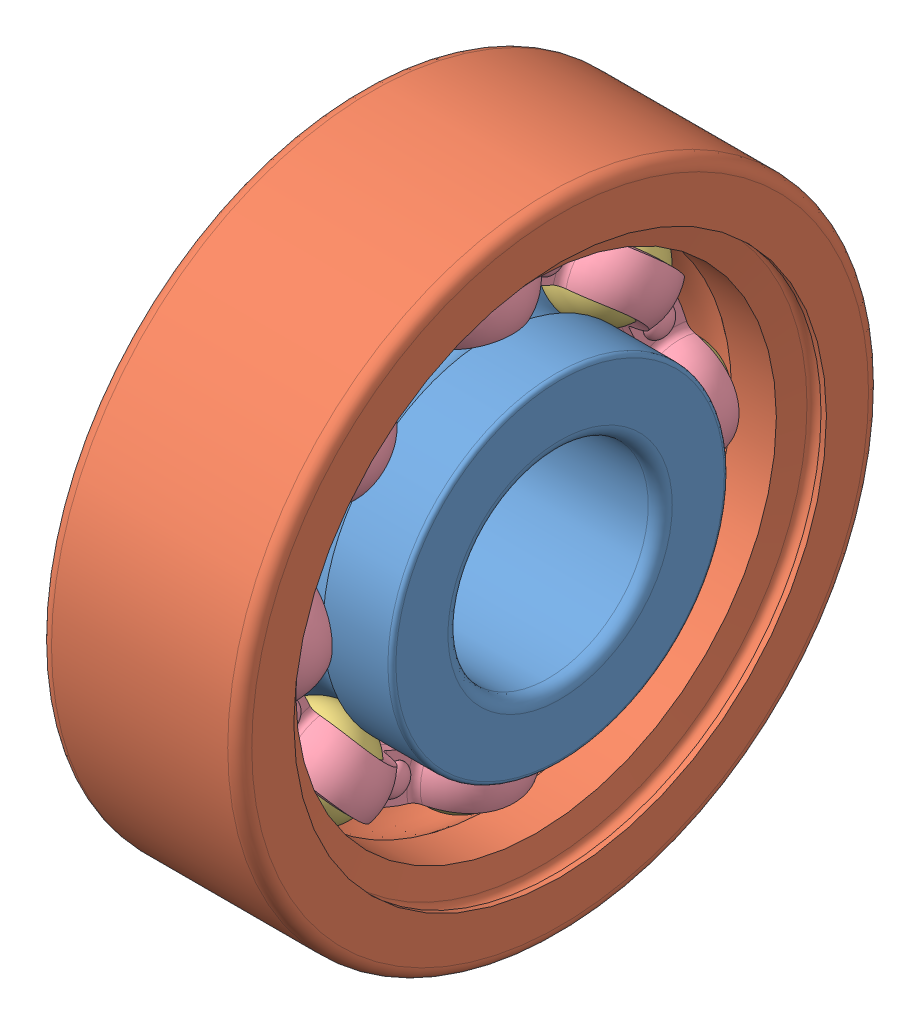
SolidWorks assembly SKF 625, configuration SKF 625. Lengths in mm.
Overall size (5 16 16).
11 component instances, 4 part files, 4 mates.
Components (placement in the parent):
- SKF 625 Inner Race^SKF 625-1: SKF 625 Inner Race^SKF 625 [Default] at origin size (5 8.4 8.4) (virtual)
- SKF 625 Outer Race^SKF 625-1: SKF 625 Outer Race^SKF 625 [Default] at origin size (5 16 16) (virtual)
- SKF 625 Ball^SKF 625-1: SKF 625 Ball^SKF 625 [Default] at origin size (2.38 2.38 2.38) (virtual)
- SKF 625 Ball^SKF 625-2: SKF 625 Ball^SKF 625 [Default] x (1 0 0) z (0 0.707107 0.707107) size (2.38 2.38 2.38) (virtual)
- SKF 625 Ball^SKF 625-3: SKF 625 Ball^SKF 625 [Default] x (1 0 0) z (0 1 0) size (2.38 2.38 2.38) (virtual)
- SKF 625 Ball^SKF 625-4: SKF 625 Ball^SKF 625 [Default] x (1 0 0) z (0 0.707107 -0.707107) size (2.38 2.38 2.38) (virtual)
- SKF 625 Ball^SKF 625-5: SKF 625 Ball^SKF 625 [Default] x (1 0 0) z (0 0 -1) size (2.38 2.38 2.38) (virtual)
- SKF 625 Ball^SKF 625-6: SKF 625 Ball^SKF 625 [Default] x (1 0 0) z (0 -0.707107 -0.707107) size (2.38 2.38 2.38) (virtual)
- SKF 625 Ball^SKF 625-7: SKF 625 Ball^SKF 625 [Default] x (1 0 0) z (0 -1 0) size (2.38 2.38 2.38) (virtual)
- SKF 625 Ball^SKF 625-8: SKF 625 Ball^SKF 625 [Default] x (1 0 0) z (0 -0.707107 0.707107) size (2.38 2.38 2.38) (virtual)
- SKF 625 Cage^SKF 625-1: SKF 625 Cage^SKF 625 [Default] at (2.5 0 0) x (0 0 -1) z (1 0 0) size (11.25 11.25 2.88) (virtual)
Mates (geometry in assembly coordinates):
- InPlace1: in place: plane of SKF 625 Cage^SKF 625-1 through (2.5 0 0) normal (1 0 0); moOrthogonalPlaneRef_w of SKF 625 Cage^SKF 625-1 through (-55 2.5 0) axis (0 0 1); plane of SKF 625 Cage^SKF 625-1 through (2.5 0 0) normal (0 0 -1); unknown of SKF 625 Cage^SKF 625-1
- Coincident1: coincident: plane of SKF 625 Cage^SKF 625-1; plane of assembly
- Coincident2: coincident: plane of SKF 625 Cage^SKF 625-1; moOrthogonalPlaneRef_w of assembly
- Coincident3: coincident: plane of SKF 625 Cage^SKF 625-1 through (2.5 0 0) normal (0 0 -1); moOrthogonalPlaneRef_w of assembly
